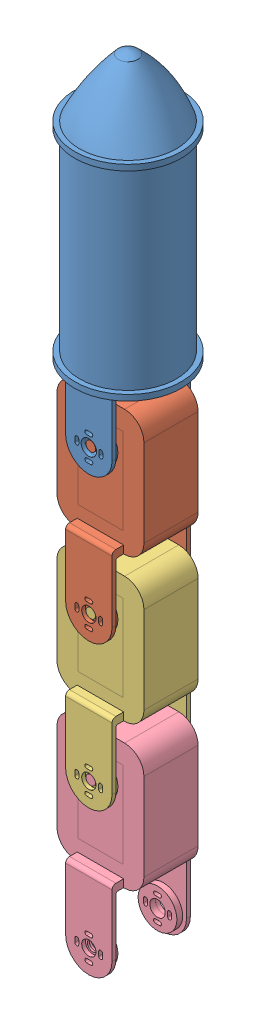
SolidWorks assembly test3_2, configuration 預設. Lengths in mm.
Overall size (55 404.08 55).
4 component instances, 4 part files, 16 mates.
Components (placement in the parent):
- base_link2-2: base_link2 [預設] at origin size (55 179.98 55)
- link1-1: link1 [預設] at (0 -157.7 0) x (0 1 0) z (0 0 -1) size (107 45 40.5)
- link2-1: link2 [預設] at (0 -232.4 0) x (0 1 0) z (0 0 -1) size (107 45 40.5)
- link3-2: link3 [預設] at (0 -307.1 0) x (0 1 0) z (0 0 -1) size (107 45 40.5)
Mates (geometry in assembly coordinates):
- 平行相距4: distance = 18.5 mm: plane of base_link2-2 through (0 -83 -18.5) normal (0 0 1); plane of assembly through (0 0 0) normal (0 0 1)
- 平行相距5: distance = 12 mm: plane of assembly through (0 0 0) normal (1 0 0); plane of base_link2-2 through (12 -53 18) normal (1 0 0)
- 平行相距6: distance = 50 mm: plane of assembly through (0 0 0) normal (0 1 0); plane of base_link2-2 through (0 -50 -0.25) normal (0 1 0)
- 同軸心2: concentric: cylinder of base_link2-2 through (0 -83 18) axis (0 0 1) radius 4; cylinder of link1-1 through (0 -83 14) axis (0 0 1) radius 2.5
- 同軸心3: concentric: cylinder of base_link2-2 through (0 -83 -20.5) axis (0 0 1) radius 4; cylinder of link1-1 through (0 -83 -19) axis (0 0 1) radius 2.5
- 平行1: parallel: plane of base_link2-2 through (12 -53 -20.5) normal (1 0 0); plane of link1-1 through (22.5 -127.7 -14) normal (1 0 0)
- 重合/共線/共點8: coincident: plane of base_link2-2 through (0 -83 -18.5) normal (0 0 1); plane of link1-1 through (0 -157.7 -18.5) normal (0 0 1)
- 同軸心4: concentric: cylinder of link1-1 through (0 -157.7 20) axis (0 0 -1) radius 3.7; cylinder of ? through (122.3295 -185.6512 7.75) axis (0 0 -1) radius 2.5
- 重合/共線/共點9: coincident: plane of link1-1 through (22.5 -127.7 -14) normal (1 0 0); unknown of ?
- 重合/共線/共點10: coincident: plane of link1-1 through (0 -67.7653 20) normal (0 0 1); line of ? through (137.5641 -185.6512 1.75) axis (0 0 -1)
- 重合/共線/共點11: coincident: plane of link1-1 through (22.5 -127.7 -14) normal (1 0 0); plane of link2-1 through (22.5 -202.4 -14) normal (1 0 0)
- 同軸心5: concentric: cylinder of link1-1 through (0 -157.7 20) axis (0 0 -1) radius 3.7; cylinder of link2-1 through (0 -157.7 14) axis (0 0 1) radius 2.5
- 重合/共線/共點12: coincident: plane of link1-1 through (0 -67.7653 14) normal (0 0 1); plane of link2-1 through (0 -142.4653 14) normal (0 0 1)
- 重合/共線/共點14: coincident: plane of link2-1 through (22.5 -202.4 -14) normal (1 0 0); plane of link3-2 through (22.5 -277.1 -14) normal (1 0 0)
- 同軸心6: concentric: cylinder of link2-1 through (0 -232.4 -18.5) axis (0 0 -1) radius 4; cylinder of link3-2 through (0 -232.4 -19) axis (0 0 1) radius 2.5; plane of link2-1; plane of link3-2
- 重合/共線/共點15: coincident: plane of link2-1 through (0 -142.4653 -14) normal (0 0 -1); plane of link3-2 through (0 -217.1653 -14) normal (0 0 -1)
